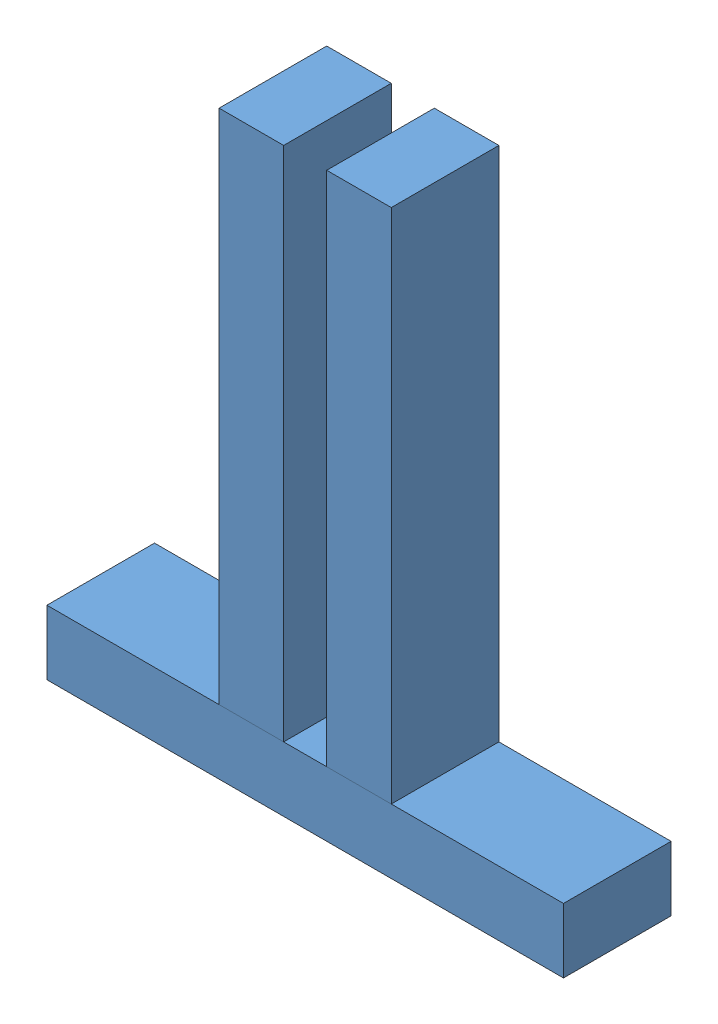
SolidWorks assembly WoodFrame, configuration Default. Lengths in mm.
Overall size (304.8 342.9 63.5).
3 component instances, 1 part files, 6 mates.
Components (placement in the parent):
- 2x3-1: 2x3 [Default] at (-9.9378 166.3799 258.5416) size (304.8 38.1 63.5)
- 2x3-2: 2x3 [Default] at (129.7622 471.1799 258.5416) x (0 -1 0) z (0 0 1) size (304.8 38.1 63.5)
- 2x3-3: 2x3 [Default] at (193.2622 471.1799 258.5416) x (0 -1 0) z (0 0 1) size (304.8 38.1 63.5)
Mates (geometry in assembly coordinates):
- Coincident1: coincident anti-aligned: plane of 2x3-1 through (294.8622 166.3799 258.5416) normal (0 1 0); plane of 2x3-2 through (129.7622 166.3799 258.5416) normal (0 -1 0)
- Coincident2: coincident aligned: plane of 2x3-1 through (294.8622 166.3799 258.5416) normal (0 0 1); plane of 2x3-2 through (129.7622 166.3799 258.5416) normal (0 0 1)
- Distance1: distance = 12.7 mm: plane of 2x3-2 through (129.7622 166.3799 258.5416) normal (1 0 0); line of assembly
- Coincident4: coincident anti-aligned: plane of 2x3-1 through (294.8622 166.3799 258.5416) normal (0 1 0); plane of 2x3-3 through (193.2622 166.3799 258.5416) normal (0 -1 0)
- Coincident5: coincident aligned: plane of 2x3-1 through (294.8622 166.3799 258.5416) normal (0 0 1); plane of 2x3-3 through (193.2622 166.3799 258.5416) normal (0 0 1)
- Distance2: distance = 25.4 mm anti-aligned: plane of 2x3-2 through (129.7622 166.3799 258.5416) normal (1 0 0); plane of 2x3-3 through (155.1622 166.3799 258.5416) normal (-1 0 0)
